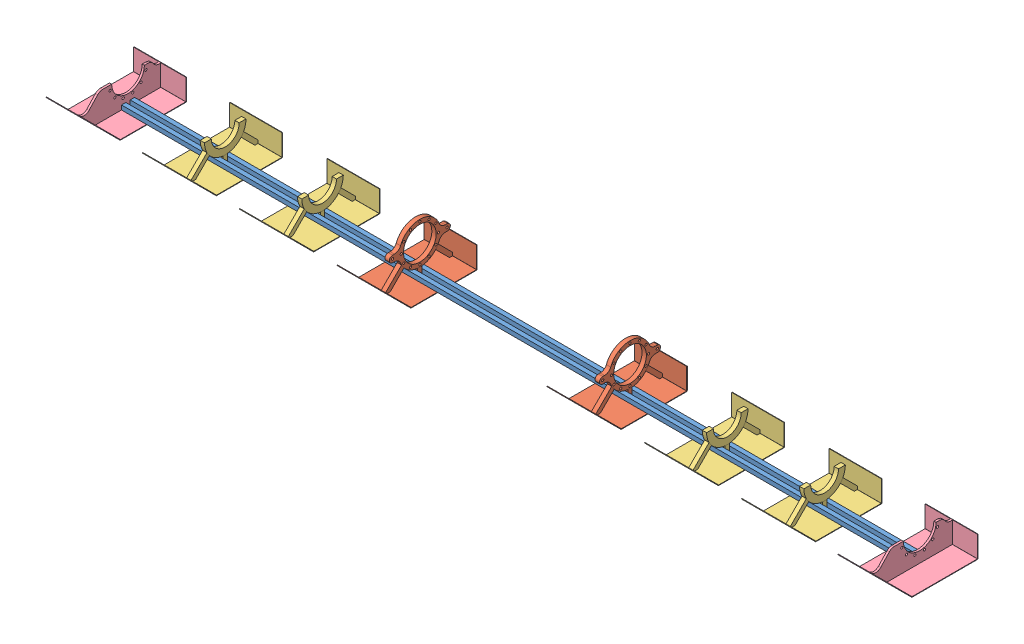
SolidWorks assembly Chassis Assembly, configuration Défaut. Lengths in mm.
Overall size (9828.53 564.8 1024.45).
10 component instances, 4 part files, 15 mates.
Components (placement in the parent):
- Crossbar-1: Crossbar [Défaut<As Machined>] at (-4596.765 0 0) size (9193.53 50.8 50.8)
- Bracket FC-1: Bracket FC [Default<As Machined>] at (1249.172 292.1 -50.8) x (0 0 1) z (-1 0 0) size (1024.45 564.8 609.6)
- Bracket Fusion-1: Bracket Fusion [Default<As Machined>] at (2382.012 292.1 -50.8) x (0 0 1) z (-1 0 0) size (1024.45 323.5 609.6)
- Bracket Fusion-2: Bracket Fusion [Default<As Machined>] at (3514.852 292.1 -50.8) x (0 0 1) z (-1 0 0) size (1024.45 323.5 609.6)
- Bracket FE-1: Bracket FE [Default<As Machined>] at (4622.165 292.1 -50.8) x (0 0 1) z (-1 0 0) size (1024.45 323.5 609.6)
- Crossbar-2: Crossbar [Défaut<As Machined>] at (-4596.765 0 -101.6) size (9193.53 50.8 50.8)
- Bracket Fusion-3: Bracket Fusion [Default<As Machined>] at (-3464.052 292.1 -50.8) x (0 0 1) z (-1 0 0) size (1024.45 323.5 609.6)
- Bracket Fusion-4: Bracket Fusion [Default<As Machined>] at (-2331.212 292.1 -50.8) x (0 0 1) z (-1 0 0) size (1024.45 323.5 609.6)
- Bracket FE-2: Bracket FE [Default<As Machined>] at (-4596.765 292.1 -50.8) x (0 0 1) z (-1 0 0) size (1024.45 323.5 609.6)
- Bracket FC-2: Bracket FC [Default<As Machined>] at (-1198.372 292.1 -50.8) x (0 0 1) z (-1 0 0) size (1024.45 564.8 609.6)
Mates (geometry in assembly coordinates):
- Coincident2: coincident anti-aligned: plane of Crossbar-1 through (0 0 0) normal (-1 0 0)
- Coincident3: coincident aligned: plane of Crossbar-1 through (-4596.765 0 0) normal (0 1 0)
- Coincident4: coincident aligned: plane of Crossbar-1 through (-4596.765 0 0) normal (0 0 1)
- Coincident5: coincident anti-aligned: plane of Crossbar-1 through (4596.765 -25.4 -25.4) normal (0 -1 0); plane of Bracket FC-1 through (1249.172 -25.4 -50.8) normal (0 1 0)
- Distance1: distance = 1198.372 mm aligned: plane of Bracket FC-1 through (1198.372 174.9809 93.8981) normal (-1 0 0); plane of Crossbar-1 through (0 0 0) normal (-1 0 0)
- Coincident7: coincident anti-aligned: plane of Crossbar-1 through (4596.765 -25.4 -25.4) normal (0 0 -1); plane of Bracket FC-1 through (1198.372 -25.4 -25.4) normal (0 0 1)
- Coincident8: coincident anti-aligned: plane of Crossbar-1 through (4596.765 -25.4 -25.4) normal (0 -1 0); plane of Bracket Fusion-1 through (2382.012 -25.4 -50.8) normal (0 1 0)
- Distance3: distance = 1132.84 mm aligned: plane of Bracket FC-1 through (1198.372 174.9809 93.8981) normal (-1 0 0); plane of Bracket Fusion-1 through (2331.212 292.1 -50.8) normal (-1 0 0)
- Coincident12: coincident anti-aligned: plane of Crossbar-1 through (4596.765 -25.4 -25.4) normal (0 0 -1); plane of Bracket Fusion-1 through (2331.212 -25.4 -25.4) normal (0 0 1)
- Distance4: distance = 1132.84 mm aligned: plane of Bracket Fusion-2 through (3464.052 292.1 -50.8) normal (-1 0 0); plane of Bracket Fusion-1 through (2331.212 292.1 -50.8) normal (-1 0 0)
- Coincident14: coincident anti-aligned: plane of Crossbar-1 through (4596.765 -25.4 -25.4) normal (0 0 -1); plane of Bracket Fusion-2 through (3464.052 -25.4 -25.4) normal (0 0 1)
- Coincident15: coincident anti-aligned: plane of Crossbar-1 through (4596.765 -25.4 -25.4) normal (0 -1 0); plane of Bracket Fusion-2 through (3514.852 -25.4 -50.8) normal (0 1 0)
- Coincident16: coincident anti-aligned: plane of Crossbar-1 through (4596.765 0 0) normal (1 0 0); plane of Bracket FE-1 through (4596.765 292.1 -50.8) normal (-1 0 0)
- Coincident17: coincident aligned: plane of Bracket Fusion-2 through (3514.852 292.1 -437.8) normal (0 0 -1); plane of Bracket FE-1 through (4622.165 292.1 -437.8) normal (0 0 -1)
- Coincident18: coincident anti-aligned: plane of Crossbar-1 through (4596.765 -25.4 -25.4) normal (0 -1 0); plane of Bracket FE-1 through (4622.165 -25.4 -50.8) normal (0 1 0)
